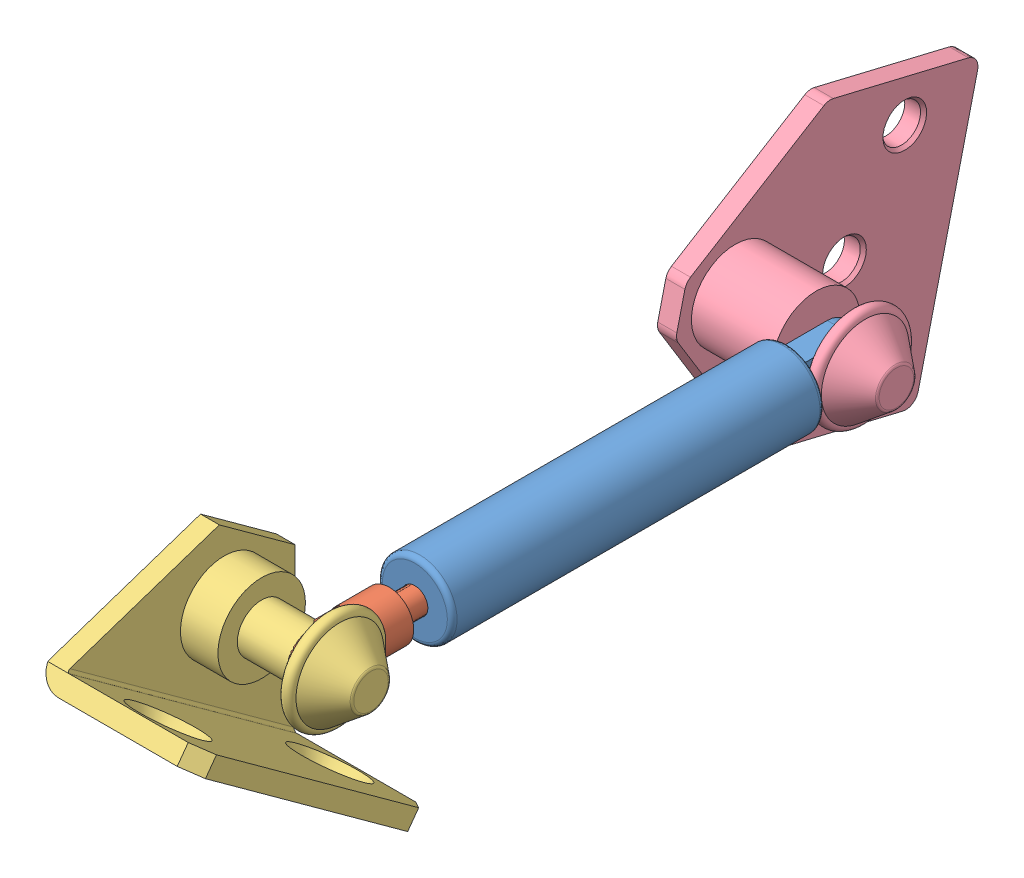
SolidWorks assembly 9517K111, configuration Default. Lengths in mm.
4 component instances, 4 part files, 7 mates.
Components (placement in the parent):
- 9417K111 Body-1: 9417K111 Body [9417K111-B] at (8.4567 -10.6015 50.6444) size (11.94 11.94 71.83)
- 9417K111 Rod-2: 9417K111 Rod [9417K111-R] at (8.4567 -10.6015 54.7084) size (7.87 7.87 58.09)
- 9416K260-1: 9416K260 [9416K260] at (-9.0113 -22.7378 88.5427) x (0 -0.587689 -0.809087) z (1 0 0) size (45 24 26.5)
- 9416K25-1: 9416K25 [9416K25] at (-11.3553 -12.914 -14.0108) x (0 0.972544 -0.232719) z (0 -0.232719 -0.972544) size (44.96 28.84 43.94)
Mates (geometry in assembly coordinates):
- Concentric1: concentric anti-aligned: cylinder of 9417K111 Body-1 through (8.4567 -10.6015 105.6354) axis (0 0 1) radius 2.0828; cylinder of 9417K111 Rod-2 through (8.4567 -10.6015 67.7894) axis (0 0 -1) radius 2.032
- Coincident1: coincident aligned: plane of 9417K111 Body-1 through (10.4887 -10.6015 -4.3466) normal (1 0 0); plane of 9417K111 Rod-2 through (10.4887 -6.6645 73.6314) normal (1 0 0)
- Distance1: distance = 80.01 mm: cylinder of 9417K111 Rod-2 through (2.4877 -10.6015 79.7274) axis (1 0 0) radius 2.032; cylinder of 9417K111 Body-1 through (10.4887 -10.6015 -4.3466) axis (-1 0 0) radius 2.032
- Concentric3: concentric aligned: cylinder of 9417K111 Body-1 through (10.4887 -10.6015 -4.3466) axis (-1 0 0) radius 2.032; cylinder of 9416K25-1 through (10.4887 -10.6015 -4.3466) axis (-1 0 0) radius 1.9558
- Coincident2: coincident anti-aligned: plane of 9417K111 Body-1 through (10.4887 -10.6015 -4.3466) normal (1 0 0); plane of 9416K25-1 through (10.4887 -8.5538 -4.5295) normal (-1 0 0)
- Concentric4: concentric anti-aligned: cylinder of 9417K111 Rod-2 through (2.4877 -10.6015 79.7274) axis (1 0 0) radius 2.032; cylinder of 9416K260-1 through (10.4887 -10.6015 79.7274) axis (-1 0 0) radius 3.9
- Coincident4: coincident anti-aligned: plane of 9417K111 Rod-2 through (10.4887 -6.6645 73.6314) normal (1 0 0); plane of 9416K260-1 through (10.4887 -10.2345 83.836) normal (-1 0 0)
